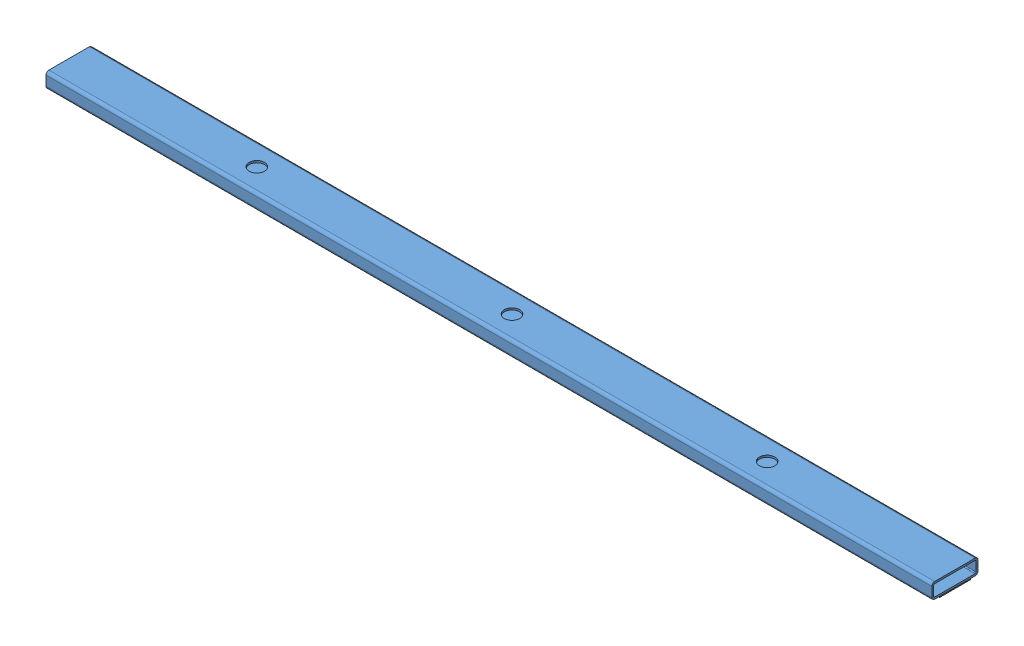
SolidWorks assembly GE-20048, configuration red. Lengths in mm.
Overall size (1460.5 26.99 76.2).
2 component instances, 2 part files, 6 mates.
Components (placement in the parent):
- GE-20053-1: GE-20053 [GE-20053-red] at origin size (1460.5 25.4 76.2)
- Hook_2_57-50-1: Hook_2_57-50 [Default] at (-730.25 -1.5875 25.4)
Mates (geometry in assembly coordinates):
- Coincident1: coincident anti-aligned: plane of GE-20053-1 through (730.25 0 -33.3248) normal (0 -1 0); plane of Hook_2_57-50-1 through (-730.25 0 25.4) normal (0 1 0)
- Width1: width anti-aligned: plane of GE-20053-1 through (730.25 20.6248 38.1) normal (0 0 1); plane of GE-20053-1 through (730.25 20.6248 -38.1) normal (0 0 -1); plane of Hook_2_57-50-1 through (-730.25 0 -25.4) normal (0 0 -1); plane of Hook_2_57-50-1 through (-730.25 0 25.4) normal (0 0 1)
- Coincident2: coincident aligned: plane of GE-20053-1 through (730.25 20.6248 -33.3248) normal (1 0 0); plane of Hook_2_57-50-1 through (730.25 0 25.4) normal (1 0 0)
- Coincident3: coincident aligned: plane of GE-20053-1 through (0 0 0) normal (0 0 1)
- Coincident4: coincident aligned: plane of GE-20053-1 through (0 0 0) normal (0 1 0)
- Coincident5: coincident aligned: plane of GE-20053-1 through (0 0 0) normal (1 0 0)
